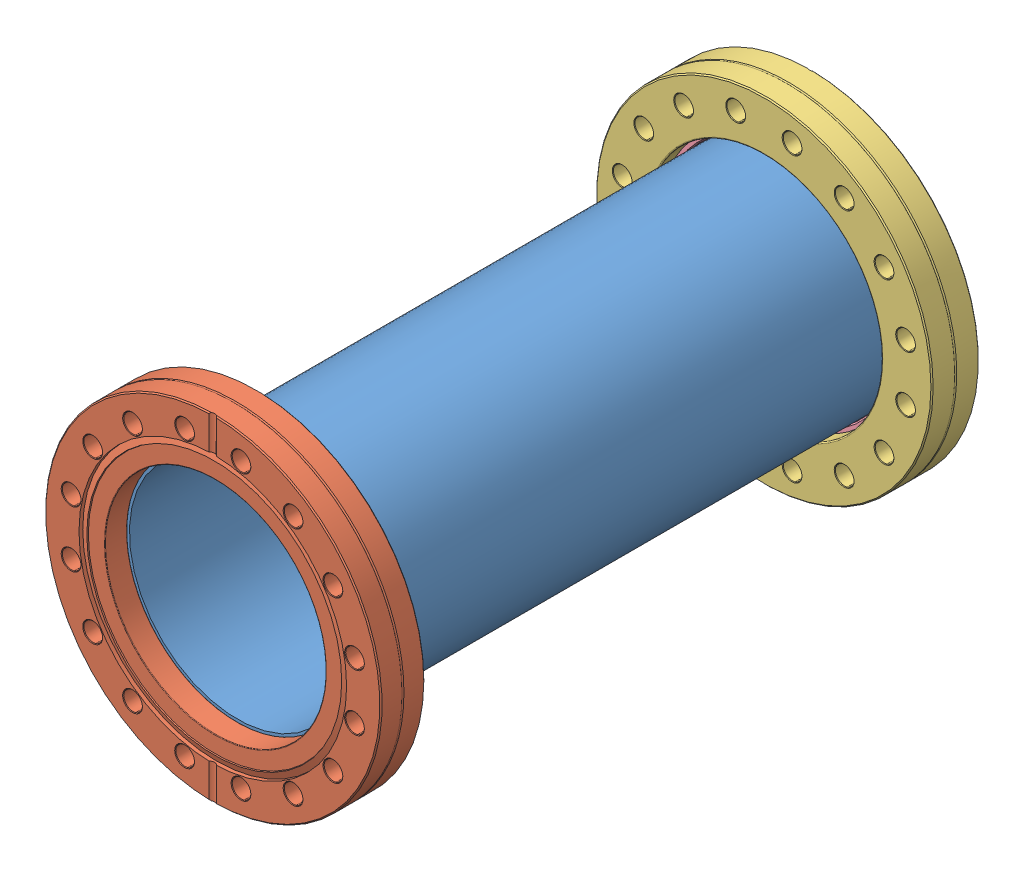
SolidWorks assembly TSP nipple_fn-0600, configuration Default. Lengths in mm.
Overall size (151.64 151.64 269.92).
6 component instances, 4 part files, 0 mates.
Components (placement in the parent):
- A0001731-1: A0001731 [Default] at origin size (151.64 151.64 258.78)
  - P0001632-1: P0001632 [Default] at (0 0 -124.968) x (0 1 0) z (0 0 -1) size (101.6 101.6 247.55)
  - P0000235-1: P0000235 [Default] at origin size (151.64 151.64 19.95)
- A0000657-1: A0000657 [Default] at (0 0 -238.506) x (1 0 0) z (0 0 -1) size (151.64 151.64 21.38)
  - P0000448-1: P0000448 [Default] at (0 0 10.668) x (-1 0 0) z (0 0 -1) size (151.64 151.64 21.38)
  - P0000507-1: P0000507 [Default] at (0 0 13.8557) size (120.5 120.5 13.64)
